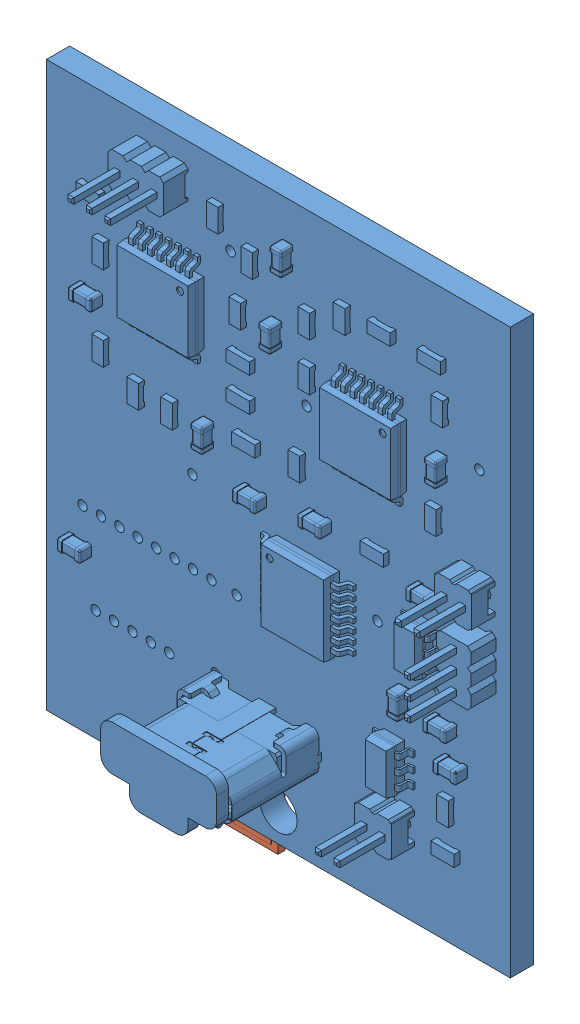
SolidWorks assembly Ensamblaje6, configuration Predeterminado. Lengths in mm.
Overall size (32 42.5 10.99).
2 component instances, 2 part files, 2 mates.
Components (placement in the parent):
- EMG_STEP-1: EMG_STEP [Default] at (-170.9819 141.6612 34.6919) size (32 38.88 9.83)
- nRF-1: nRF [Predeterminado] at (-30.0019 -1.9588 32.8028) size (12 18 0.8)
Mates (geometry in assembly coordinates):
- Concéntrica1: concentric anti-aligned: circle of EMG_STEP-1; circle of nRF-1
- Distancia1: distance = 1.7 mm: line of nRF-1 through (-30.0019 -11.8907 33.3028) axis (0 1 0); line of EMG_STEP-1 through (-30.9819 22.5412 34.6919) axis (0 -1 0)
